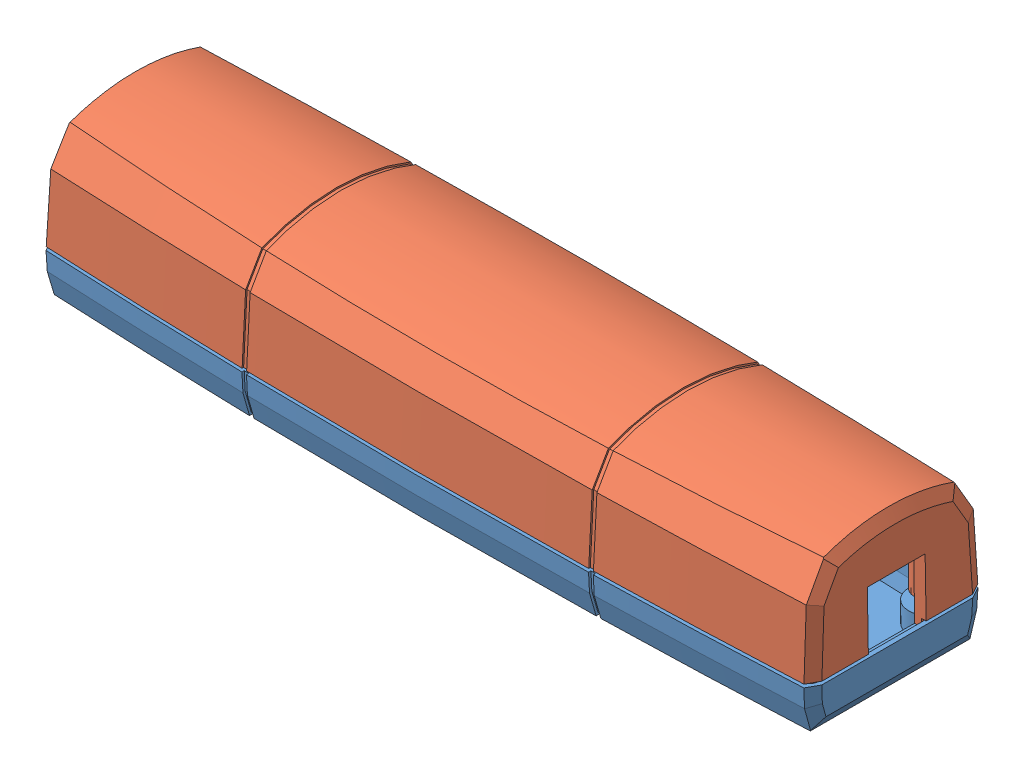
SolidWorks assembly HSG1001, configuration Default. Lengths in mm.
Overall size (127.04 25.41 31.78).
2 component instances, 2 part files, 6 mates.
Components (placement in the parent):
- HSG1001-1-1: HSG1001-1 [Default] x (1 0 0) z (0 1 0) size (127.04 31.78 6.96)
- HSG1001-2-1: HSG1001-2 [Default] x (1 0 0) z (0 1 0) size (127.03 31.72 19.32)
Mates (geometry in assembly coordinates):
- Coincident1: coincident aligned: plane of HSG1001-1-1 through (0 0 0) normal (0 1 0); plane of assembly through (0 0 0) normal (0 1 0)
- Coincident2: coincident anti-aligned: plane of HSG1001-1-1 through (0 0 0) normal (0 0 -1); plane of assembly through (0 0 0) normal (0 0 1)
- Coincident3: coincident aligned: plane of HSG1001-1-1; plane of assembly through (0 0 0) normal (1 0 0)
- Coincident4: coincident aligned: plane of HSG1001-2-1; plane of assembly through (0 0 0) normal (1 0 0)
- Coincident5: coincident anti-aligned: plane of HSG1001-2-1 through (0 0 0) normal (0 0 -1); plane of assembly through (0 0 0) normal (0 0 1)
- Coincident6: coincident anti-aligned: plane of HSG1001-1-1 through (0 -0.762 1254.111) normal (0 1 0); plane of HSG1001-2-1 through (0 -0.762 1254.111) normal (0 -1 0)
